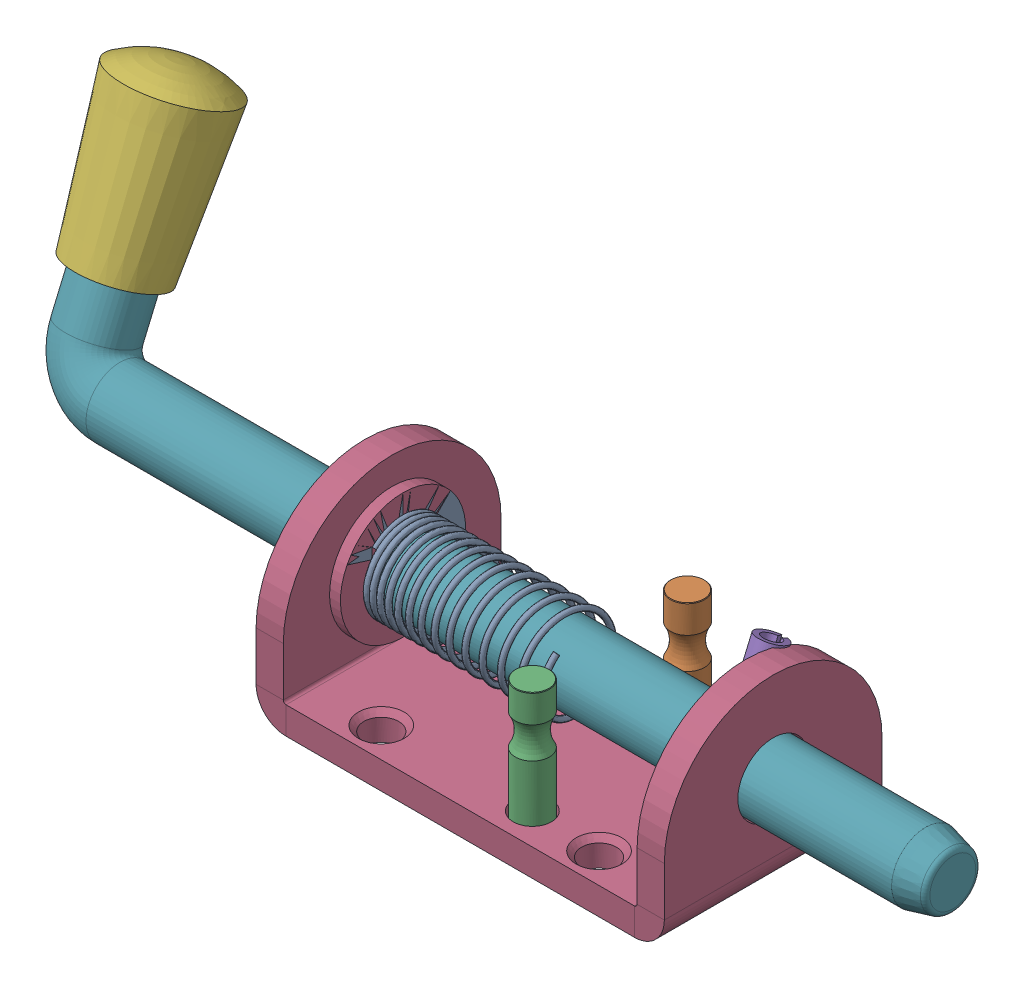
SolidWorks assembly Vedruriiv 165X40X60mm, configuration Default. Lengths in mm.
Overall size (170 63.99 47.23).
2 component instances, 2 part files, 0 mates.
Components (placement in the parent):
- 12.5D SLL Body-1: 12.5D SLL Body [Default] at (-5.2218 18.2824 77.7593) size (75 34.5 40)
- 12.5D SLL Bolt-1: 12.5D SLL Bolt [Default] at (102.7782 36.2824 57.7593) x (1 0 0) z (0 0.394284 0.918989) size (170 53.75 20)
